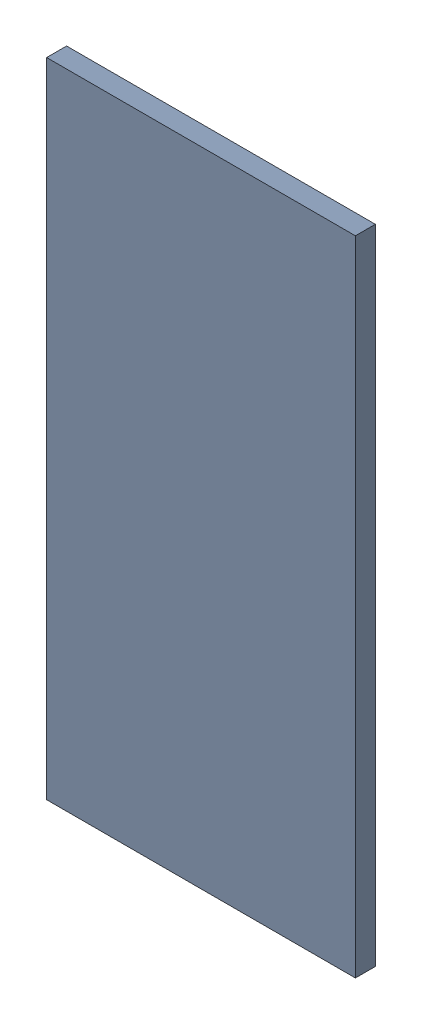
SolidWorks assembly Pad ADXL345-1(23mm,58.097mm) on Top Layer, configuration Predeterminado. Lengths in mm.
Overall size (0.55 1.15 0.04).
2 component instances, 1 part files, 0 mates.
Components (placement in the parent):
- Pad ADXL345-1(23mm,58.097mm) on Top Layer-1-1: Pad ADXL345-1(23mm,58.097mm) on Top Layer-1 [Predeterminado] at (-68.317 -44.187 -0.0457) size (0.55 1.15 0.04)
  - Pad ADXL345-1(23mm,58.097mm) on Top Layer-Part-1-1: Pad ADXL345-1(23mm,58.097mm) on Top Layer-Part-1 [Predeterminado] at origin size (0.55 1.15 0.04)
